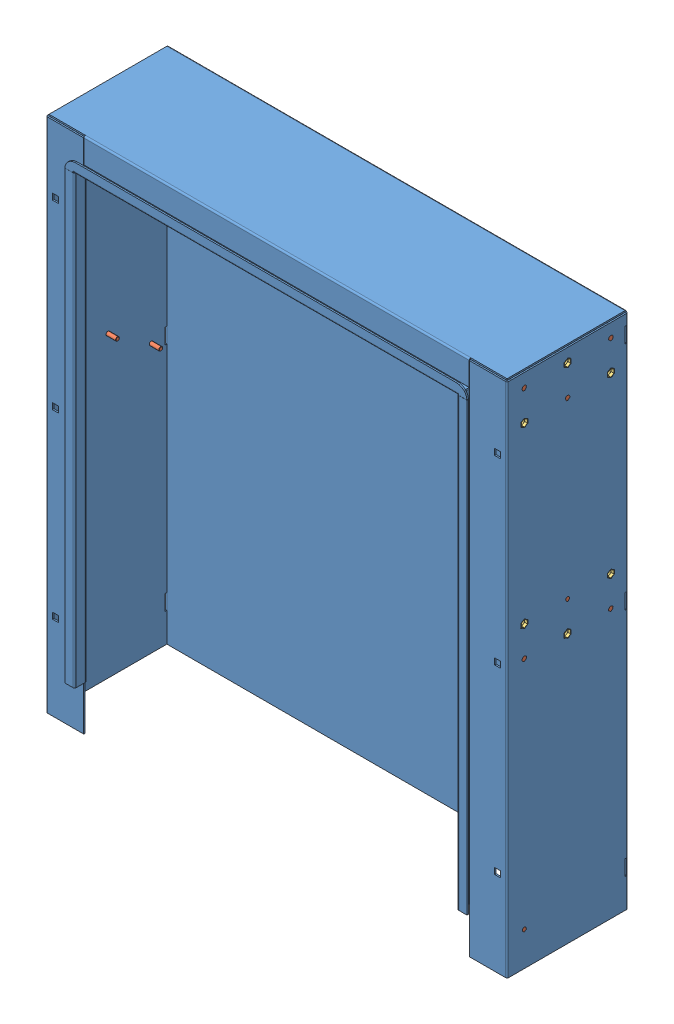
SolidWorks assembly ENCLOSURE-CORPS, configuration Défaut. Lengths in mm.
Overall size (610 685 174).
20 component instances, 3 part files, 32 mates.
Components (placement in the parent):
- ENCLOSURE-CORPS-1: ENCLOSURE-CORPS [Défaut] at (-52.7739 32.3739 0) size (610 685 174)
- FHSM5X15-2: FHSM5X15 [PEM FHS-M5-15 ---N] at (252.2261 354.8739 135.2) x (-1 0 0) z (0 0.924225 0.381849) size (15 6.5 6.5)
- FHSM5X15-3: FHSM5X15 [PEM FHS-M5-15 ---N] at (252.2261 354.8739 20.8) x (-1 0 0) z (0 0.924225 0.381849) size (15 6.5 6.5)
- FHSM5X15-4: FHSM5X15 [PEM FHS-M5-15 ---N] at (252.2261 84.8739 78) x (-1 0 0) z (0 0.924225 0.381849) size (15 6.5 6.5)
- FHSM5X15-5: FHSM5X15 [PEM FHS-M5-15 ---N] at (252.2261 44.8739 135.2) x (-1 0 0) z (0 0.924225 0.381849) size (15 6.5 6.5)
- FHSM5X15-6: FHSM5X15 [PEM FHS-M5-15 ---N] at (252.2261 44.8739 20.8) x (-1 0 0) z (0 0.924225 0.381849) size (15 6.5 6.5)
- FHSM5X15-7: FHSM5X15 [PEM FHS-M5-15 ---N] at (252.2261 314.8739 78) x (-1 0 0) z (0 0.924225 0.381849) size (15 6.5 6.5)
- FHSM5X15-8: FHSM5X15 [PEM FHS-M5-15 ---N] at (-357.7739 354.8739 20.8) size (15 6.5 6.5)
- FHSM5X15-9: FHSM5X15 [PEM FHS-M5-15 ---N] at (-357.7739 354.8739 135.2) size (15 6.5 6.5)
- FHSM5X15-10: FHSM5X15 [PEM FHS-M5-15 ---N] at (-357.7739 44.8739 20.8) size (15 6.5 6.5)
- FHSM5X15-11: FHSM5X15 [PEM FHS-M5-15 ---N] at (-357.7739 84.8739 78) size (15 6.5 6.5)
- FHSM5X15-12: FHSM5X15 [PEM FHS-M5-15 ---N] at (-357.7739 44.8739 135.2) size (15 6.5 6.5)
- INSERTHM6X30BIN-1: INSERTHM6X30BIN [Défaut] at (232.4261 354.8739 78) x (0 -0.866025 -0.5) z (0 -0.5 0.866025) size (13.8 19.8 13.8)
- INSERTHM6X30BIN-2: INSERTHM6X30BIN [Défaut] at (232.4261 44.8739 78) x (0 -0.866025 -0.5) z (0 -0.5 0.866025) size (13.8 19.8 13.8)
- INSERTHM6X30BIN-3: INSERTHM6X30BIN [Défaut] at (232.4261 314.8739 135.2) x (0 -0.866025 -0.5) z (0 -0.5 0.866025) size (13.8 19.8 13.8)
- INSERTHM6X30BIN-4: INSERTHM6X30BIN [Défaut] at (232.4261 314.8739 20.8) x (0 -0.866025 -0.5) z (0 -0.5 0.866025) size (13.8 19.8 13.8)
- INSERTHM6X30BIN-5: INSERTHM6X30BIN [Défaut] at (232.4261 84.8739 135.2) x (0 -0.866025 -0.5) z (0 -0.5 0.866025) size (13.8 19.8 13.8)
- INSERTHM6X30BIN-6: INSERTHM6X30BIN [Défaut] at (232.4261 84.8739 20.8) x (0 -0.866025 -0.5) z (0 -0.5 0.866025) size (13.8 19.8 13.8)
- FHSM5X15-13: FHSM5X15 [PEM FHS-M5-15 ---N] at (252.2261 -265.1261 135.2) x (-1 0 0) z (0 0.924225 0.381849) size (15 6.5 6.5)
- FHSM5X15-14: FHSM5X15 [PEM FHS-M5-15 ---N] at (-357.7739 -265.1261 135.2) size (15 6.5 6.5)
Mates (geometry in assembly coordinates):
- Coaxiale21: concentric aligned: cylinder of ENCLOSURE-CORPS-1 through (-357.7749 354.8739 135.2) axis (1 0 0) radius 2.5; cylinder of FHSM5X15-2 through (252.2261 354.8739 135.2) axis (1 0 0) radius 2.9775
- Coïncidente21: coincident aligned: plane of ENCLOSURE-CORPS-1 through (252.2261 -310.1261 156) normal (1 0 0); plane of FHSM5X15-2 through (252.2261 354.8739 135.2) normal (1 0 0)
- Coaxiale31: concentric aligned: cylinder of ENCLOSURE-CORPS-1 through (-357.7749 354.8739 20.8) axis (1 0 0) radius 2.5; cylinder of FHSM5X15-3 through (252.2261 354.8739 20.8) axis (1 0 0) radius 2.9775
- Coïncidente31: coincident aligned: plane of ENCLOSURE-CORPS-1 through (252.2261 -310.1261 156) normal (1 0 0); plane of FHSM5X15-3 through (252.2261 354.8739 20.8) normal (1 0 0)
- Coaxiale41: concentric aligned: cylinder of ENCLOSURE-CORPS-1 through (-357.7749 84.8739 78) axis (1 0 0) radius 2.5; cylinder of FHSM5X15-4 through (252.2261 84.8739 78) axis (1 0 0) radius 2.9775
- Coïncidente41: coincident aligned: plane of ENCLOSURE-CORPS-1 through (252.2261 -310.1261 156) normal (1 0 0); plane of FHSM5X15-4 through (252.2261 84.8739 78) normal (1 0 0)
- Coaxiale51: concentric aligned: cylinder of ENCLOSURE-CORPS-1 through (-357.7749 44.8739 135.2) axis (1 0 0) radius 2.5; cylinder of FHSM5X15-5 through (252.2261 44.8739 135.2) axis (1 0 0) radius 2.9775
- Coïncidente51: coincident aligned: plane of ENCLOSURE-CORPS-1 through (252.2261 -310.1261 156) normal (1 0 0); plane of FHSM5X15-5 through (252.2261 44.8739 135.2) normal (1 0 0)
- Coaxiale61: concentric aligned: cylinder of ENCLOSURE-CORPS-1 through (-357.7749 44.8739 20.8) axis (1 0 0) radius 2.5; cylinder of FHSM5X15-6 through (252.2261 44.8739 20.8) axis (1 0 0) radius 2.9775
- Coïncidente61: coincident aligned: plane of ENCLOSURE-CORPS-1 through (252.2261 -310.1261 156) normal (1 0 0); plane of FHSM5X15-6 through (252.2261 44.8739 20.8) normal (1 0 0)
- Coaxiale71: concentric aligned: cylinder of ENCLOSURE-CORPS-1 through (-357.7749 314.8739 78) axis (1 0 0) radius 2.5; cylinder of FHSM5X15-7 through (252.2261 314.8739 78) axis (1 0 0) radius 2.9775
- Coïncidente71: coincident aligned: plane of ENCLOSURE-CORPS-1 through (252.2261 -310.1261 156) normal (1 0 0); plane of FHSM5X15-7 through (252.2261 314.8739 78) normal (1 0 0)
- Coaxiale81: concentric aligned: cylinder of ENCLOSURE-CORPS-1 through (252.2271 354.8739 20.8) axis (-1 0 0) radius 2.5; cylinder of FHSM5X15-8 through (-357.7739 354.8739 20.8) axis (-1 0 0) radius 2.9775
- Coïncidente81: coincident aligned: plane of ENCLOSURE-CORPS-1 through (-357.7739 -310.1261 0) normal (-1 0 0); plane of FHSM5X15-8 through (-357.7739 354.8739 20.8) normal (-1 0 0)
- Coaxiale91: concentric aligned: cylinder of ENCLOSURE-CORPS-1 through (252.2271 354.8739 135.2) axis (-1 0 0) radius 2.5; cylinder of FHSM5X15-9 through (-357.7739 354.8739 135.2) axis (-1 0 0) radius 2.9775
- Coïncidente91: coincident aligned: plane of ENCLOSURE-CORPS-1 through (-357.7739 -310.1261 0) normal (-1 0 0); plane of FHSM5X15-9 through (-357.7739 354.8739 135.2) normal (-1 0 0)
- Coaxiale101: concentric aligned: cylinder of ENCLOSURE-CORPS-1 through (252.2271 44.8739 20.8) axis (-1 0 0) radius 2.5; cylinder of FHSM5X15-10 through (-357.7739 44.8739 20.8) axis (-1 0 0) radius 2.9775
- Coïncidente101: coincident aligned: plane of ENCLOSURE-CORPS-1 through (-357.7739 -310.1261 0) normal (-1 0 0); plane of FHSM5X15-10 through (-357.7739 44.8739 20.8) normal (-1 0 0)
- Coaxiale111: concentric aligned: cylinder of ENCLOSURE-CORPS-1 through (252.2271 84.8739 78) axis (-1 0 0) radius 2.5; cylinder of FHSM5X15-11 through (-357.7739 84.8739 78) axis (-1 0 0) radius 2.9775
- Coïncidente111: coincident aligned: plane of ENCLOSURE-CORPS-1 through (-357.7739 -310.1261 0) normal (-1 0 0); plane of FHSM5X15-11 through (-357.7739 84.8739 78) normal (-1 0 0)
- Coaxiale121: concentric aligned: cylinder of ENCLOSURE-CORPS-1 through (252.2271 44.8739 135.2) axis (-1 0 0) radius 2.5; cylinder of FHSM5X15-12 through (-357.7739 44.8739 135.2) axis (-1 0 0) radius 2.9775
- Coïncidente121: coincident aligned: plane of ENCLOSURE-CORPS-1 through (-357.7739 -310.1261 0) normal (-1 0 0); plane of FHSM5X15-12 through (-357.7739 44.8739 135.2) normal (-1 0 0)
- Coïncidente122: coincident aligned: plane of ENCLOSURE-CORPS-1 through (252.2261 -310.1261 156) normal (1 0 0); plane of INSERTHM6X30BIN-1 through (252.2261 352.3711 76.555) normal (1 0 0)
- Coaxiale122: concentric aligned: cylinder of INSERTHM6X30BIN-1 through (240.1209 354.8739 78) axis (1 0 0) radius 4.5; circle of assembly
- Parallèle1: parallel anti-aligned: line of ENCLOSURE-CORPS-1 through (252.2261 352.2181 73.4) axis (0 1 0); line of INSERTHM6X30BIN-1 through (252.2261 357.7607 73) axis (0 -1 0)
- Coïncidente126: coincident aligned: plane of ENCLOSURE-CORPS-1 through (252.2261 -310.1261 156) normal (1 0 0); plane of INSERTHM6X30BIN-3 through (252.2261 312.3711 133.755) normal (1 0 0)
- Coaxiale123: concentric aligned: cylinder of INSERTHM6X30BIN-3 through (240.1209 314.8739 135.2) axis (1 0 0) radius 4.5; circle of assembly
- Parallèle2: parallel anti-aligned: line of ENCLOSURE-CORPS-1 through (252.2261 312.2181 130.6) axis (0 1 0); line of INSERTHM6X30BIN-3 through (252.2261 317.7607 130.2) axis (0 -1 0)
- Coaxiale1241: concentric aligned: cylinder of ENCLOSURE-CORPS-1 through (-357.7749 -265.1261 135.2) axis (1 0 0) radius 2.5; cylinder of FHSM5X15-13 through (252.2261 -265.1261 135.2) axis (1 0 0) radius 2.9775
- Coïncidente1271: coincident aligned: plane of ENCLOSURE-CORPS-1 through (252.2261 -310.1261 156) normal (1 0 0); plane of FHSM5X15-13 through (252.2261 -265.1261 135.2) normal (1 0 0)
- Coïncidente1281: coincident aligned: plane of ENCLOSURE-CORPS-1 through (-357.7739 -310.1261 0) normal (-1 0 0); plane of FHSM5X15-14 through (-357.7739 -265.1261 135.2) normal (-1 0 0)
- Coaxiale1242: concentric aligned: cylinder of ENCLOSURE-CORPS-1 through (252.2271 -265.1261 135.2) axis (-1 0 0) radius 2.5; cylinder of FHSM5X15-14 through (-357.7739 -265.1261 135.2) axis (-1 0 0) radius 2.5
